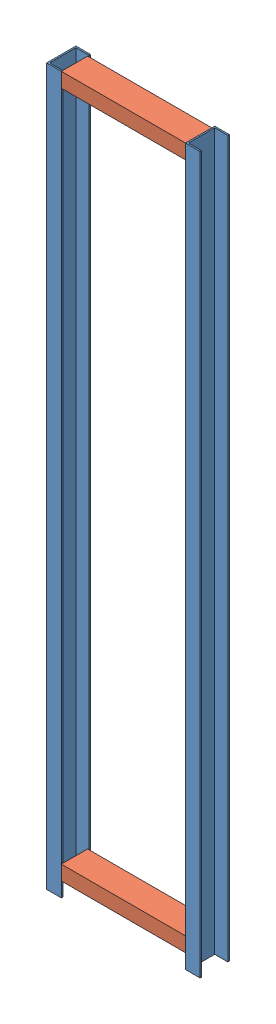
SolidWorks assembly SECONDSTAGE, configuration Default. Lengths in mm.
Overall size (266.7 1244.6 50.8).
4 component instances, 2 part files, 4 mates.
Components (placement in the parent):
- SECONDSTAGELONG-1: SECONDSTAGELONG [Default] at (327.3453 -14.8464 1050.1391) size (25.4 1244.6 50.8)
- SECONDSTAGELONG-2: SECONDSTAGELONG [Default] at (568.6453 -14.8464 1050.1391) size (25.4 1244.6 50.8)
- SECONDSTAGECROSS-1: SECONDSTAGECROSS [Default] at (352.7453 1229.7536 1050.1391) x (0 -1 0) z (0 0 1) size (25.4 215.9 45.72)
- SECONDSTAGECROSS-2: SECONDSTAGECROSS [Default] at (352.7453 35.9536 1050.1391) x (0 -1 0) z (0 0 1) size (25.4 215.9 45.72)
Mates (geometry in assembly coordinates):
- Coincident3: coincident aligned: plane of SECONDSTAGELONG-1 through (327.3453 1229.7536 1050.1391) normal (0 1 0); plane of SECONDSTAGELONG-2 through (568.6453 1229.7536 1050.1391) normal (0 1 0)
- Coincident7: coincident aligned: plane of SECONDSTAGELONG-1 through (327.3453 1229.7536 1050.1391) normal (0 0 1); plane of SECONDSTAGECROSS-2 through (568.6453 35.9536 1050.1391) normal (0 0 1)
- Distance2: distance = 25.4 mm aligned: plane of SECONDSTAGELONG-2 through (568.6453 -14.8464 1050.1391) normal (0 -1 0); plane of SECONDSTAGECROSS-2 through (568.6453 10.5536 1050.1391) normal (0 -1 0)
- Coincident9: coincident anti-aligned: plane of SECONDSTAGELONG-2 through (568.6453 1229.7536 1050.1391) normal (-1 0 0); plane of SECONDSTAGECROSS-2 through (568.6453 35.9536 1050.1391) normal (1 0 0)
